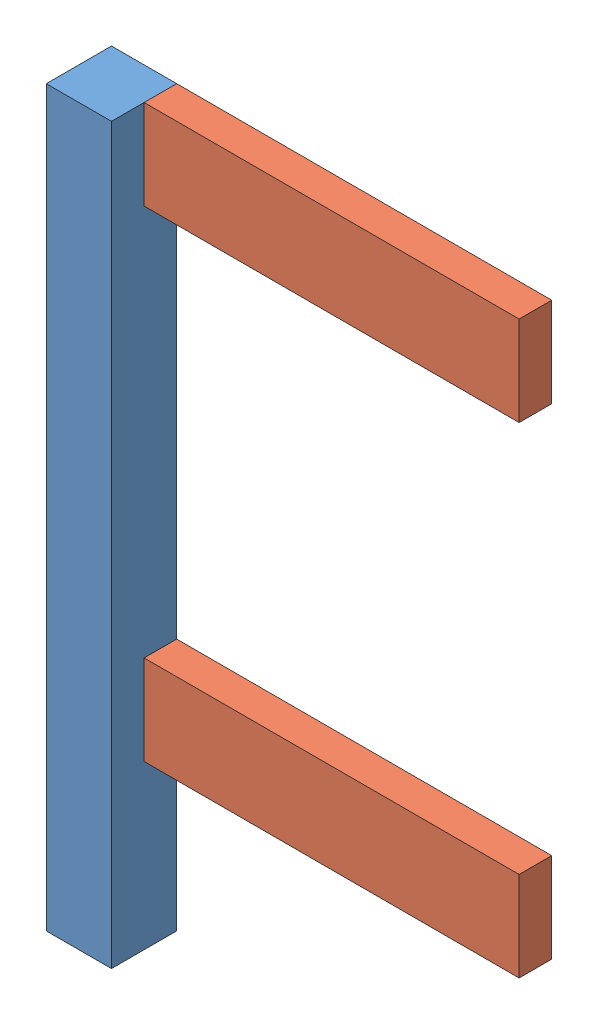
SolidWorks assembly Сб1, configuration По умолчанию. Lengths in mm.
Overall size (270 450 40).
3 component instances, 2 part files, 7 mates.
Components (placement in the parent):
- Ножка-1: Ножка [По умолчанию] at origin size (40 450 40)
- перекладина-1: перекладина [По умолчанию] at (250 422.5 -10) x (0 1 0) z (0 0 1) size (55 230 20)
- перекладина-2: перекладина [По умолчанию] at (250 127.5 -10) x (0 1 0) z (0 0 1) size (55 230 20)
Mates (geometry in assembly coordinates):
- Совпадение1: coordinate: point of Ножка-1; point of assembly
- Совпадение2: coincident aligned: plane of Ножка-1 through (0 450 0) normal (0 1 0); plane of перекладина-1 through (20 450 -20) normal (0 1 0)
- Совпадение3: coincident aligned: plane of Ножка-1 through (-20 450 -20) normal (0 0 -1); plane of перекладина-1 through (20 395 -20) normal (0 0 -1)
- Совпадение4: coincident anti-aligned: plane of Ножка-1 through (20 450 -20) normal (1 0 0); plane of перекладина-1 through (20 422.5 -10) normal (-1 0 0)
- Совпадение5: coincident aligned: plane of перекладина-1 through (20 395 -20) normal (0 0 -1); plane of перекладина-2 through (20 221.5696 -20) normal (0 0 -1)
- Совпадение6: coincident aligned: plane of перекладина-1 through (250 422.5 -10) normal (1 0 0); plane of перекладина-2 through (250 249.0696 -10) normal (1 0 0)
- Расстояние1: distance = 240 mm anti-aligned: plane of перекладина-2 through (20 155 -20) normal (0 1 0); plane of перекладина-1 through (20 395 -20) normal (0 -1 0)
